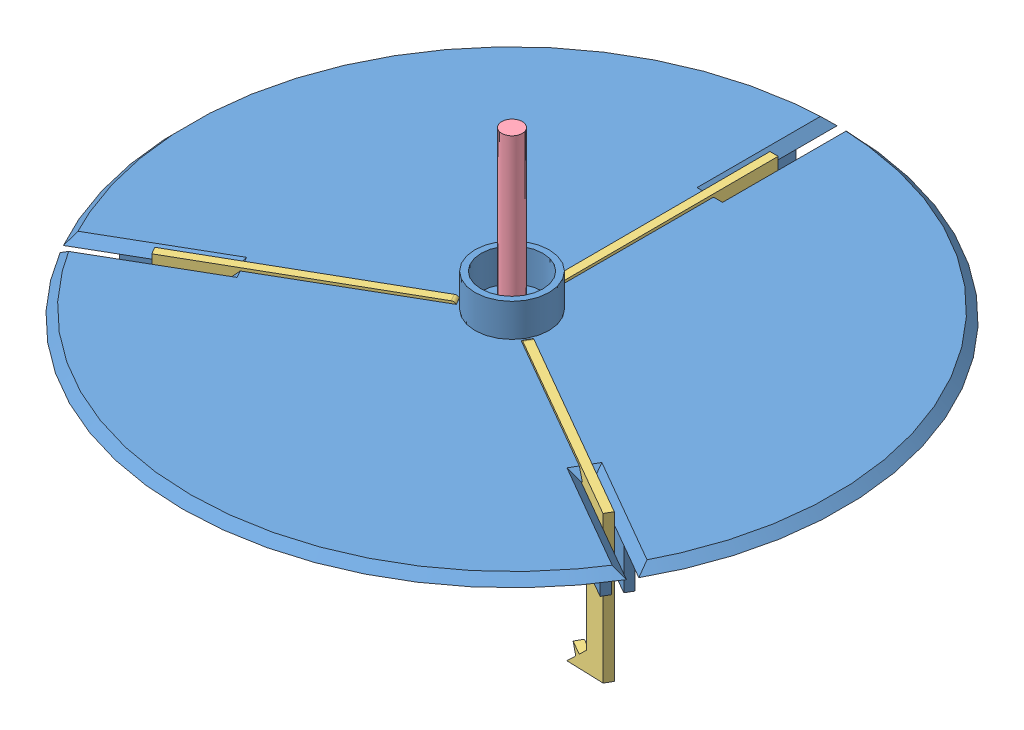
SolidWorks assembly gripping arm, configuration Default. Lengths in mm.
Overall size (160 84.88 159.99).
6 component instances, 4 part files, 8 mates.
Components (placement in the parent):
- holder-1: holder [Default] at (57.5052 102.868 110.8238) size (160 20 159.99)
- pneumatic to arm-1: pneumatic to arm [Default] at (57.5052 102.7858 110.8238) x (0.999262 0 -0.038423) z (-0.038423 0 -0.999262) size (54.95 10 48.9)
- finger-1: finger [Default] at (49.7132 56.0449 116.5927) x (-0.866022 0.002696 0.499998) z (-0.002335 -0.999996 0.001348) size (54.2 2 47.28)
- rod-1: rod [Default] at (57.5052 93.0562 110.8238) x (0.882577 0 0.470169) z (-0.470169 0 0.882577) size (5 50 5)
- finger-2: finger [Default] at (56.4052 56.0449 101.1912) x (0 0.002696 -0.999996) z (0 -0.999996 -0.002696) size (54.2 2 47.28)
- finger-3: finger [Default] at (66.3973 56.0449 114.6875) x (0.866022 0.002696 0.499998) z (0.002335 -0.999996 0.001348) size (54.2 2 47.28)
Mates (geometry in assembly coordinates):
- Parallel2: parallel: plane of holder-1 through (60.6052 92.868 60.8238) normal (1 0 0); plane of pneumatic to arm-1
- Concentric6: concentric aligned: circle of holder-1; circle of rod-1
- Concentric7: concentric anti-aligned: circle of holder-1; circle of pneumatic to arm-1
- Parallel7: parallel aligned: plane of holder-1 through (99.2565 92.868 138.5085) normal (-0.5 0 0.866025); plane of pneumatic to arm-1 through (64.2154 92.7858 118.2382) normal (-0.5 0 0.866025)
- Lock2: lock: unknown of pneumatic to arm-1; unknown of rod-1
- Coincident11: coincident anti-aligned: circle of holder-1; circle of finger-1
- Tangent2: tangent anti-aligned: cylinder of pneumatic to arm-1 through (39.7387 97.7858 129.0881) axis (-0.5 0 -0.866025) radius 2; plane of finger-1 through (35.8249 99.7858 122.3018) normal (-0.002335 -0.999996 0.001348)
- PathMate2: path: point of pneumatic to arm-1; line of assembly
